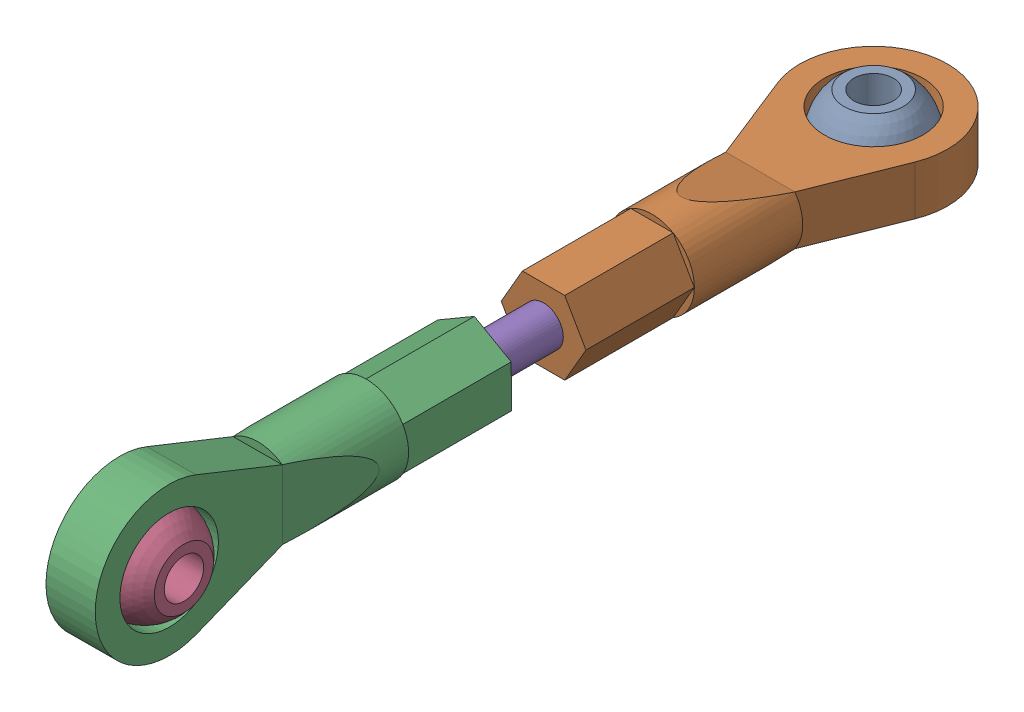
SolidWorks assembly Ball joint, configuration Default. Lengths in mm.
Overall size (7.5 7.52 44.5).
5 component instances, 3 part files, 8 mates.
Components (placement in the parent):
- Ball for ball joint-1: Ball for ball joint [Default] at (1.3949 8.6043 -18.3615) x (-0.93238 0 -0.36148) z (0.36148 0 -0.93238) size (5 4 5)
- Ball joint-1: Ball joint [Default] at (1.3949 7.3543 -18.3615) size (7.5 4.3 20.5)
- Ball joint-2: Ball joint [Default] at (2.6449 8.6112 18.6385) x (0.005503 -0.999985 0) z (0 0 -1) size (7.5 4.3 20.5)
- Ball for ball joint-2: Ball for ball joint [Default] at (1.3949 8.6043 18.6385) x (0.001791 -0.3254 0.945575) z (0.005204 -0.94556 -0.325405) size (5 4 5)
- Screw for ball joint-1: Screw for ball joint [Default] at (1.3949 8.6043 7.3885) x (0.657492 -0.753462 0) z (0.753462 0.657492 0) size (2 14.5 2)
Mates (geometry in assembly coordinates):
- Width1: width aligned: plane of Ball for ball joint-1 through (5.0097 6.6043 -27.6853) normal (0 -1 0); plane of Ball joint-1 through (5.0097 10.6043 -27.6853) normal (0 1 0); plane of Ball for ball joint-1 through (1.3949 7.3543 -18.3615) normal (0 -1 0); plane of Ball joint-1 through (1.3949 9.8543 -18.3615) normal (0 1 0)
- Concentric3: concentric: sphere of Ball for ball joint-1; cylinder of Ball joint-1 through (1.3949 9.8543 -18.3615) axis (0 -1 0) radius 2.5
- Width2: width aligned: plane of Ball for ball joint-2 through (3.4469 -0.8403 15.3844) normal (0.999985 0.005503 0); plane of Ball joint-2 through (-0.5531 -0.8623 15.3844) normal (-0.999985 -0.005503 0); plane of Ball for ball joint-2 through (2.6449 8.6112 18.6385) normal (0.999985 0.005503 0); plane of Ball joint-2 through (0.1449 8.5974 18.6385) normal (-0.999985 -0.005503 0)
- Concentric4: concentric: cylinder of Ball joint-2 through (0.1449 8.5974 18.6385) axis (0.999985 0.005503 0) radius 2.5; sphere of Ball for ball joint-2
- Concentric5: concentric anti-aligned: cylinder of Ball joint-1 through (1.3949 8.6043 -1.6115) axis (0 0 -1) radius 1; cylinder of Screw for ball joint-1 through (1.3949 8.6043 -7.1115) axis (0 0 1) radius 1
- Coincident2: coincident anti-aligned: plane of Ball joint-1 through (1.3949 8.6043 -7.1115) normal (0 0 1); plane of Screw for ball joint-1 through (1.3949 8.6043 -7.1115) normal (0 0 -1)
- Concentric6: concentric aligned: cylinder of Ball joint-2 through (1.3949 8.6043 1.8885) axis (0 0 1) radius 1; cylinder of Screw for ball joint-1 through (1.3949 8.6043 -7.1115) axis (0 0 1) radius 1
- Coincident3: coincident anti-aligned: plane of Ball joint-2 through (1.3949 8.6043 7.3885) normal (0 0 -1); plane of Screw for ball joint-1 through (1.3949 8.6043 7.3885) normal (0 0 1)
